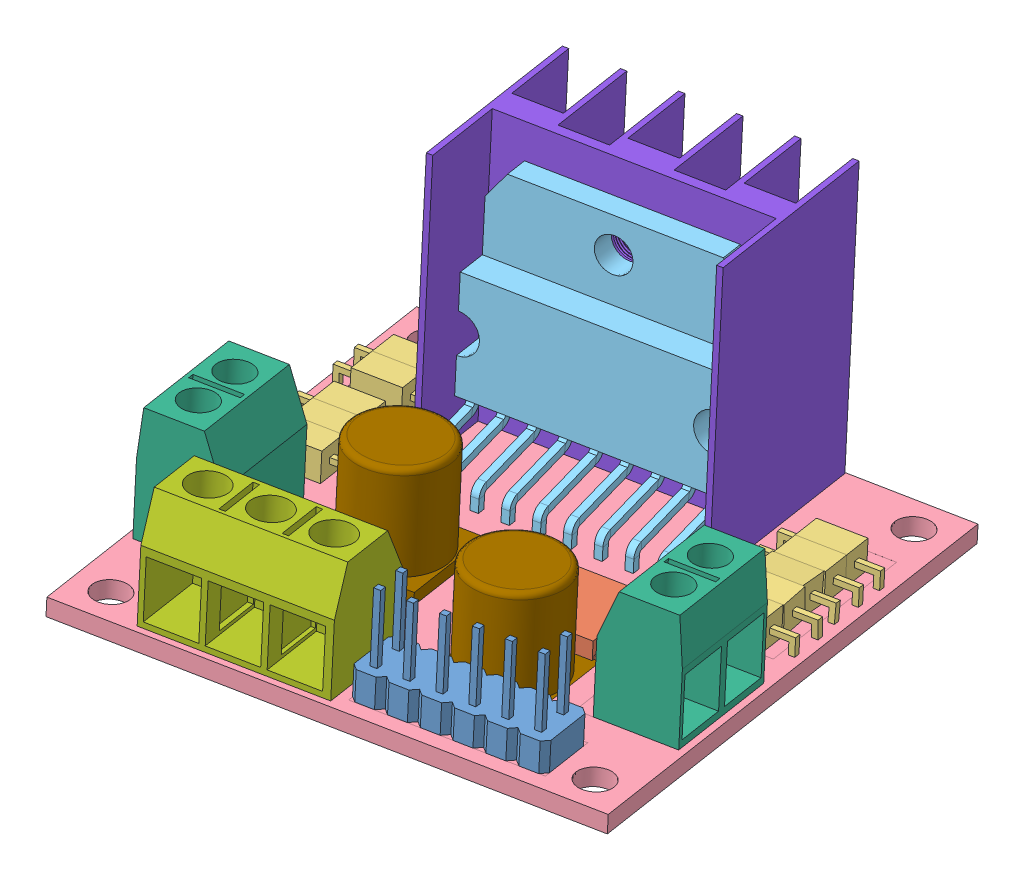
SolidWorks assembly L298N_LAPRAP, configuration Default. Lengths in mm.
Overall size (51.35 26.63 51.35).
21 component instances, 10 part files, 39 mates.
Components (placement in the parent):
- Cam_chan_pin-1: Cam_chan_pin [Default] at (54.1565 13.169 16.3726) x (-0.979684 0.006124 0.200454) z (0.006124 -0.998154 0.060429) size (15.29 5.05 8.5)
- chip_L298-1: chip_L298 [Default] at (41.3918 9.7439 2.4625) x (0.200454 0.060429 0.977838) z (-0.006124 0.998154 -0.060429) size (6.9 12.02 1.5)
- DIODE-1: DIODE [Default] at (16.3005 10.4551 -3.9332) x (0.979684 -0.006124 -0.200454) z (0.200454 0.060429 0.977838) size (8 3 2.5)
- L298N-1: L298N [Default] at (-6.6936 10.7695 24.2768) x (-0.979684 0.006124 0.200454) z (0.006124 -0.998154 0.060429) size (43.5 43.5 1.5)
- L298N_to-1: L298N_to [Default] at (42.1403 23.0295 -12.9731) x (-0.979684 0.006124 0.200454) z (-0.200454 -0.060429 -0.977838) size (20.33 21.27 9.26)
- Regulator_Capacitor-1: Regulator_Capacitor [Default] at (-14.7993 69.7487 119.7369)
- Screw_terminal_2way-1: Screw_terminal_2way [Default] at (52.5529 9.6161 -0.7796) x (0.979684 -0.006124 -0.200454) z (0.200454 0.060429 0.977838) size (6.62 10.2 10)
- screw_terminal_3way-1: screw_terminal_3way [Default] at (109.9866 32.3529 368.9638) x (0.200454 0.060429 0.977838) z (-0.979684 0.006124 0.200454) size (8 10 15)
- Tan_nhiet-1: Tan_nhiet [Default] at (31.6821 32.7021 -14.4949) x (-0.979684 0.006124 0.200454) z (0.006124 -0.998154 0.060429) size (23 16 24)
- Tu_dien-1: Tu_dien [Default] at (29.229 10.8618 5.6122) x (0.979684 -0.006124 -0.200454) z (0.006124 -0.998154 0.060429) size (8.3 8.3 9.3)
- Screw_terminal_2way-2: Screw_terminal_2way [Default] at (19.6045 10.4389 16.1506) x (-0.979684 0.006124 0.200454) z (-0.200454 -0.060429 -0.977838) size (6.62 10.2 10)
- Tu_dien-2: Tu_dien [Default] at (43.6889 10.1815 9.4571) x (0.979684 -0.006124 -0.200454) z (0.006124 -0.998154 0.060429) size (8.3 8.3 9.3)
- DIODE-2: DIODE [Default] at (15.3984 10.1831 -8.3335) x (0.979684 -0.006124 -0.200454) z (0.200454 0.060429 0.977838) size (8 3 2.5)
- DIODE-3: DIODE [Default] at (16.8016 10.6061 -1.4886) x (0.979684 -0.006124 -0.200454) z (0.200454 0.060429 0.977838) size (8 3 2.5)
- DIODE-6: DIODE [Default] at (17.3027 10.7572 0.956) x (0.979684 -0.006124 -0.200454) z (0.200454 0.060429 0.977838) size (8 3 2.5)
- DIODE-7: DIODE [Default] at (14.8973 10.0321 -10.7781) x (0.979684 -0.006124 -0.200454) z (0.200454 0.060429 0.977838) size (8 3 2.5)
- DIODE-8: DIODE [Default] at (48.7073 9.9446 -15.6488) x (0.979684 -0.006124 -0.200454) z (0.200454 0.060429 0.977838) size (8 3 2.5)
- DIODE-9: DIODE [Default] at (50.7099 10.5484 -5.8795) x (0.979684 -0.006124 -0.200454) z (0.200454 0.060429 0.977838) size (8 3 2.5)
- DIODE-10: DIODE [Default] at (49.2084 10.0957 -13.2042) x (0.979684 -0.006124 -0.200454) z (0.200454 0.060429 0.977838) size (8 3 2.5)
- DIODE-11: DIODE [Default] at (50.2494 10.5473 -8.4149) x (0.979684 -0.006124 -0.200454) z (0.200454 -0.00062 0.979703) size (8 3 2.5)
- DIODE-12: DIODE [Default] at (49.6136 10.2544 -10.6623) x (0.979684 -0.006124 -0.200454) z (0.199706 0.121252 0.972325) size (8 3 2.5)
Mates (geometry in assembly coordinates):
- Coincident2: coincident aligned: line of L298N-1 through (44.699 9.1594 -7.5272) axis (-0.979684 0.006124 0.200454); line of Tan_nhiet-1 through (44.699 9.1594 -7.5272) axis (-0.979684 0.006124 0.200454)
- Coincident3: coincident aligned: line of L298N-1 through (18.959 8.3334 -18.5621) axis (0.200454 0.060429 0.977838); line of Tan_nhiet-1 through (18.959 8.3334 -18.5621) axis (0.200454 0.060429 0.977838)
- Coincident4: coincident anti-aligned: circle of L298N_to-1; circle of Tan_nhiet-1
- Parallel1: parallel anti-aligned: line of L298N_to-1 through (23.7047 29.8193 -11.6588) axis (0.979684 -0.006124 -0.200454); line of Tan_nhiet-1 through (42.659 32.6952 -15.7221) axis (-0.979684 0.006124 0.200454)
- Coincident14: coincident anti-aligned: line of L298N-1 through (57.8013 10.2001 8.3351) axis (-0.979684 0.006124 0.200454); line of Screw_terminal_2way-1 through (51.3136 10.2407 9.6625) axis (0.979684 -0.006124 -0.200454)
- Coincident15: coincident anti-aligned: line of L298N-1 through (55.7967 9.5958 -1.4433) axis (0.200454 0.060429 0.977838); line of Screw_terminal_2way-1 through (57.8013 10.2001 8.3351) axis (-0.200454 -0.060429 -0.977838)
- Coincident17: coincident anti-aligned: line of L298N-1 through (16.3606 10.4592 16.8143) axis (0.979684 -0.006124 -0.200454); line of Screw_terminal_2way-2 through (22.8483 10.4186 15.4869) axis (-0.979684 0.006124 0.200454)
- Coincident18: coincident aligned: line of L298N-1 through (14.3561 9.8549 7.0359) axis (0.200454 0.060429 0.977838); line of Screw_terminal_2way-2 through (14.3561 9.8549 7.0359) axis (0.200454 0.060429 0.977838)
- Coincident19: coincident aligned: line of L298N-1 through (22.359 10.4587 16.1983) axis (0.200454 0.060429 0.977838); line of screw_terminal_3way-1 through (22.359 10.4587 16.1983) axis (0.200454 0.060429 0.977838)
- Coincident20: coincident aligned: line of L298N-1 through (23.9626 10.9421 24.021) axis (0.979684 -0.006124 -0.200454); line of screw_terminal_3way-1 through (23.9626 10.9421 24.021) axis (0.979684 -0.006124 -0.200454)
- Coincident21: coincident aligned: line of L298N-1 through (46.9795 9.9224 4.844) axis (0.200454 0.060429 0.977838); line of Tu_dien-2 through (46.9227 9.9053 4.5672) axis (0.200454 0.060429 0.977838)
- Parallel3: parallel anti-aligned: line of L298N-1 through (39.96 10.3084 11.9317) axis (0.834484 0.038399 0.549693); line of Tu_dien-2 through (42.5871 9.4462 13.9724) axis (-0.834484 -0.038399 -0.549693)
- Coincident23: coincident anti-aligned: line of L298N-1 through (42.8749 10.4425 13.8519) axis (0.979684 -0.006124 -0.200454); line of Tu_dien-2 through (48.5865 10.4068 12.6832) axis (-0.979684 0.006124 0.200454)
- Coincident30: coincident aligned: line of L298N-1 through (32.5257 9.6046 1.0596) axis (0.200454 0.060429 0.977838); line of Tu_dien-1 through (32.4689 9.5875 0.7827) axis (0.200454 0.060429 0.977838)
- Coincident31: coincident anti-aligned: line of L298N-1 through (28.4212 10.1247 10.0674) axis (0.979684 -0.006124 -0.200454); line of Tu_dien-1 through (34.1327 10.089 8.8988) axis (-0.979684 0.006124 0.200454)
- Coincident32: coincident aligned: line of L298N-1 through (14.8725 9.679 4.0775) axis (0.979684 -0.006124 -0.200454); line of DIODE-6 through (15.8521 9.6728 3.877) axis (0.979684 -0.006124 -0.200454)
- Coincident34: coincident anti-aligned: line of L298N-1 through (16.8643 8.7721 -11.1034) axis (0.200454 0.060429 0.977838); line of DIODE-6 through (19.7709 9.6483 3.0752) axis (-0.200454 -0.060429 -0.977838)
- Coincident40: coincident anti-aligned: line of L298N-1 through (16.8643 8.7721 -11.1034) axis (0.200454 0.060429 0.977838); line of DIODE-7 through (17.3654 8.9232 -8.6588) axis (-0.200454 -0.060429 -0.977838)
- Coincident41: coincident aligned: line of L298N-1 through (11.9659 8.8028 -10.1012) axis (0.979684 -0.006124 -0.200454); line of DIODE-7 through (12.9456 8.7966 -10.3016) axis (0.979684 -0.006124 -0.200454)
- Coincident44: coincident aligned: line of DIODE-3 through (15.351 9.5218 1.4324) axis (0.979684 -0.006124 -0.200454); line of DIODE-6 through (15.351 9.5218 1.4324) axis (0.979684 -0.006124 -0.200454)
- Coincident46: coincident anti-aligned: line of L298N-1 through (16.8643 8.7721 -11.1034) axis (0.200454 0.060429 0.977838); line of DIODE-3 through (19.2697 9.4973 0.6306) axis (-0.200454 -0.060429 -0.977838)
- Coincident47: coincident anti-aligned: line of L298N-1 through (16.8643 8.7721 -11.1034) axis (0.200454 0.060429 0.977838); line of DIODE-2 through (17.8666 9.0743 -6.2142) axis (-0.200454 -0.060429 -0.977838)
- Coincident48: coincident anti-aligned: line of DIODE-1 through (18.7686 9.3462 -1.814) axis (-0.200454 -0.060429 -0.977838); line of L298N-1 through (16.8643 8.7721 -11.1034) axis (0.200454 0.060429 0.977838)
- Coincident57: coincident aligned: line of Cam_chan_pin-1 through (53.37 10.4319 12.6123) axis (0.200454 0.060429 0.977838); line of L298N-1 through (53.2682 10.4012 12.1154) axis (0.200454 0.060429 0.977838)
- Parallel12: parallel anti-aligned: plane of Cam_chan_pin-1 through (54.1719 10.6736 16.5237) normal (0.006124 -0.998154 0.060429); plane of L298N-1 through (-6.6936 10.7675 24.277) normal (-0.006124 0.998154 -0.060429)
- Coincident60: coincident aligned: line of Cam_chan_pin-1 through (48.7772 10.4292 13.0343) axis (0.979684 -0.006124 -0.200454); line of L298N-1 through (38.3378 10.4945 15.1703) axis (0.979684 -0.006124 -0.200454)
- Coincident63: coincident anti-aligned: plane of DIODE-2 through (15.3984 10.1831 -8.3335) normal (-0.200454 -0.060429 -0.977838); plane of DIODE-7 through (15.3984 10.1831 -8.3335) normal (0.200454 0.060429 0.977838)
- Coincident64: coincident: point of DIODE-2; point of DIODE-7
- Coincident65: coincident aligned: line of DIODE-1 through (18.7533 11.8416 -1.965) axis (-0.979684 0.006124 0.200454); line of DIODE-3 through (18.7533 11.8416 -1.965) axis (-0.979684 0.006124 0.200454)
- Coincident66: coincident anti-aligned: line of L298N-1 through (54.1578 9.4334 -3.9607) axis (-0.979684 0.006124 0.200454); line of DIODE-9 through (49.2594 9.464 -2.9585) axis (0.979684 -0.006124 -0.200454)
- Coincident67: coincident anti-aligned: line of L298N-1 through (46.3528 8.5878 -17.1371) axis (0.200454 0.060429 0.977838); line of DIODE-9 through (49.2594 9.464 -2.9585) axis (-0.200454 -0.060429 -0.977838)
- Coincident68: coincident aligned: line of DIODE-9 through (52.6617 11.7838 -6.3559) axis (-0.979684 0.006124 0.200454); line of DIODE-11 through (52.7175 11.7835 -6.3674) axis (-0.979684 0.006124 0.200454)
- Coincident69: coincident aligned: line of DIODE-11 through (52.2164 11.785 -8.8166) axis (-0.979684 0.006124 0.200454); line of DIODE-12 through (52.0493 11.7861 -8.7824) axis (-0.979684 0.006124 0.200454)
- Coincident70: coincident aligned: line of DIODE-10 through (51.6613 11.4822 -11.236) axis (-0.979684 0.006124 0.200454); line of DIODE-12 through (51.5501 11.4829 -11.2133) axis (-0.979684 0.006124 0.200454)
- Coincident71: coincident anti-aligned: line of L298N-1 through (46.3528 8.5878 -17.1371) axis (0.200454 0.060429 0.977838); line of DIODE-10 through (47.7578 9.0113 -10.2831) axis (-0.200454 -0.060429 -0.977838)
- Coincident73: coincident aligned: line of DIODE-8 through (47.2567 8.8603 -12.7277) axis (0.979684 -0.006124 -0.200454); line of DIODE-10 through (47.2567 8.8603 -12.7277) axis (0.979684 -0.006124 -0.200454)
- Coincident75: coincident: point of DIODE-8; point of DIODE-10
- Coincident77: coincident: line of chip_L298-1 through (34.3924 9.5934 0.6853) axis (0.200454 0.060429 0.977838); line of L298N-1 through (34.647 9.6701 1.9269) axis (-0.200454 -0.060429 -0.977838)
- Parallel13: parallel anti-aligned: plane of chip_L298-1 through (41.3918 9.7439 2.4625) normal (0.006124 -0.998154 0.060429); plane of L298N-1 through (-6.6935 10.7496 24.278) normal (-0.006124 0.998154 -0.060429)
